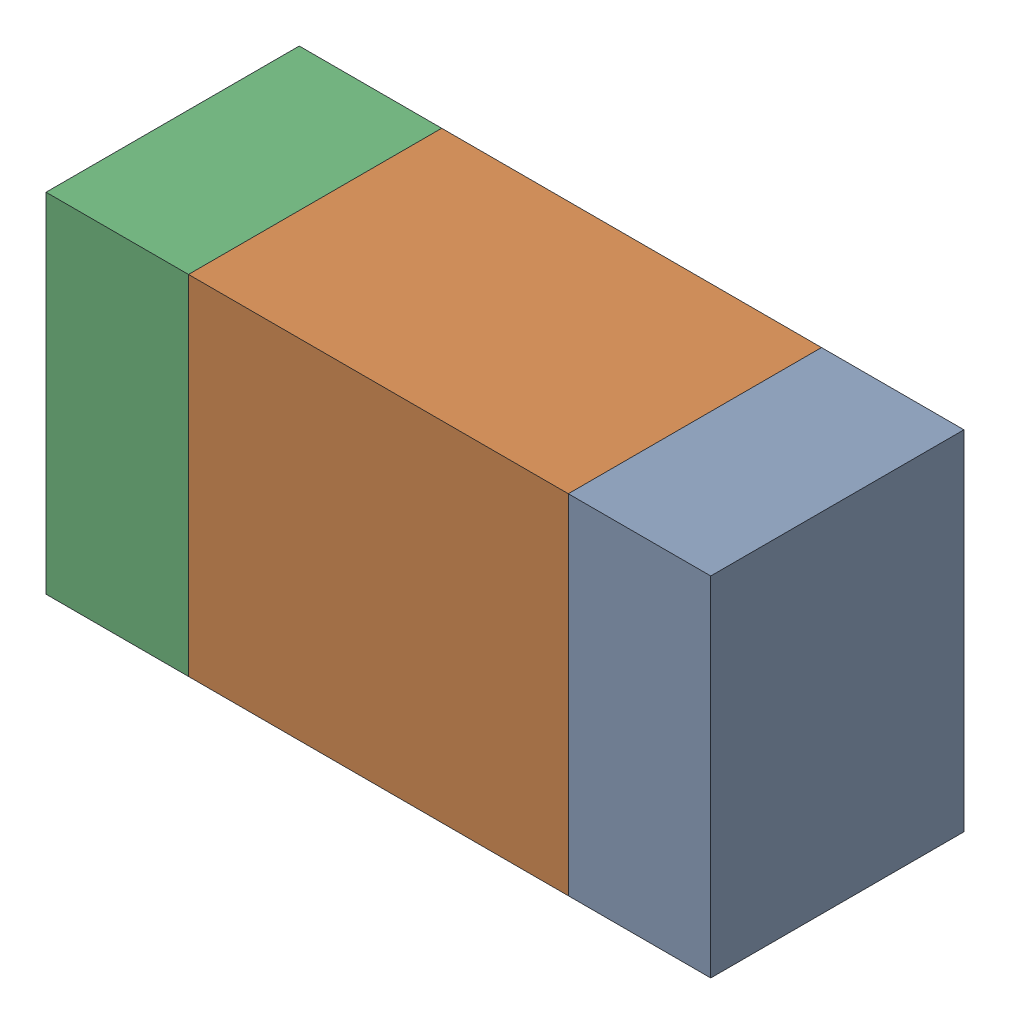
SolidWorks assembly R415PCB, configuration Default. Lengths in mm.
Overall size (1.05 0.55 0.4).
6 component instances, 2 part files, 0 mates.
Components (placement in the parent):
- 854785432-1: 854785432 [Default] at (84.7126 81.2001 0) size (0.22 0.55 0.4)
  - Extruded-1: Extruded [Default] at origin size (0.22 0.55 0.4)
- 854785568-1: 854785568 [Default] at (84.3001 81.2001 0) size (0.6 0.55 0.4)
  - Extruded_2-1: Extruded_2 [Default] at origin size (0.6 0.55 0.4)
- 854785432-2: 854785432 [Default] at (83.8876 81.2001 0) size (0.22 0.55 0.4)
  - Extruded-1: Extruded [Default] at origin size (0.22 0.55 0.4)
